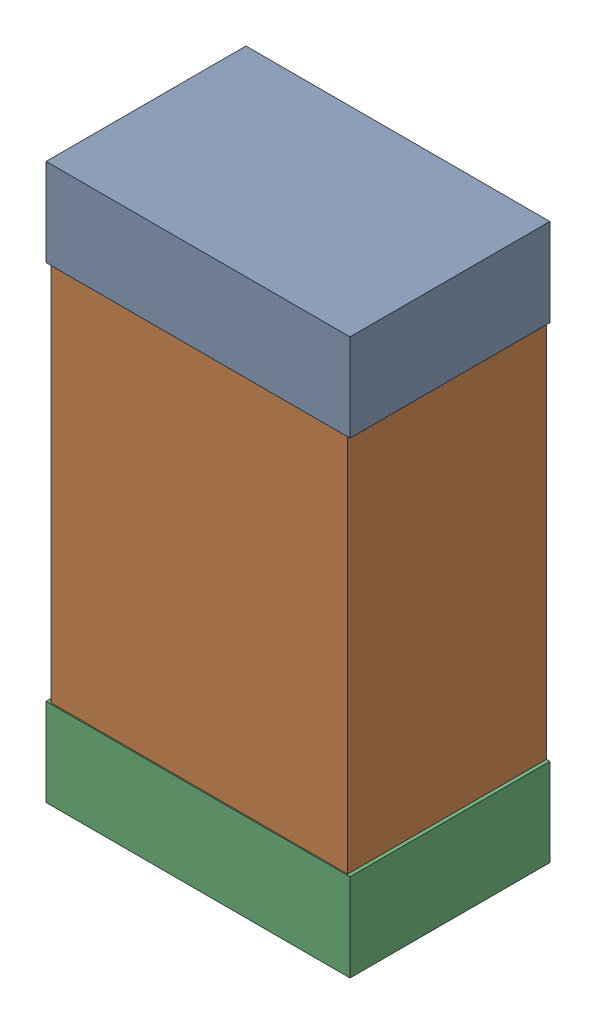
SolidWorks assembly RFBBKanaloa_v2.0.0_Power_1, configuration Default. Lengths in mm.
Overall size (1.3 2.38 0.85).
6 component instances, 2 part files, 0 mates.
Components (placement in the parent):
- 330415056-1: 330415056 [Default] at (137.8816 53.4565 0) size (1.3 0.38 0.85)
  - Extruded_2-1: Extruded_2 [Default] at origin size (1.3 0.38 0.85)
- 334787376-1: 334787376 [Default] at (137.8816 52.4565 0) size (1.27 2.2 0.85)
  - Extruded_16-1: Extruded_16 [Default] at origin size (1.27 2.2 0.85)
- 330415056-2: 330415056 [Default] at (137.8816 51.4565 0) size (1.3 0.38 0.85)
  - Extruded_2-1: Extruded_2 [Default] at origin size (1.3 0.38 0.85)
